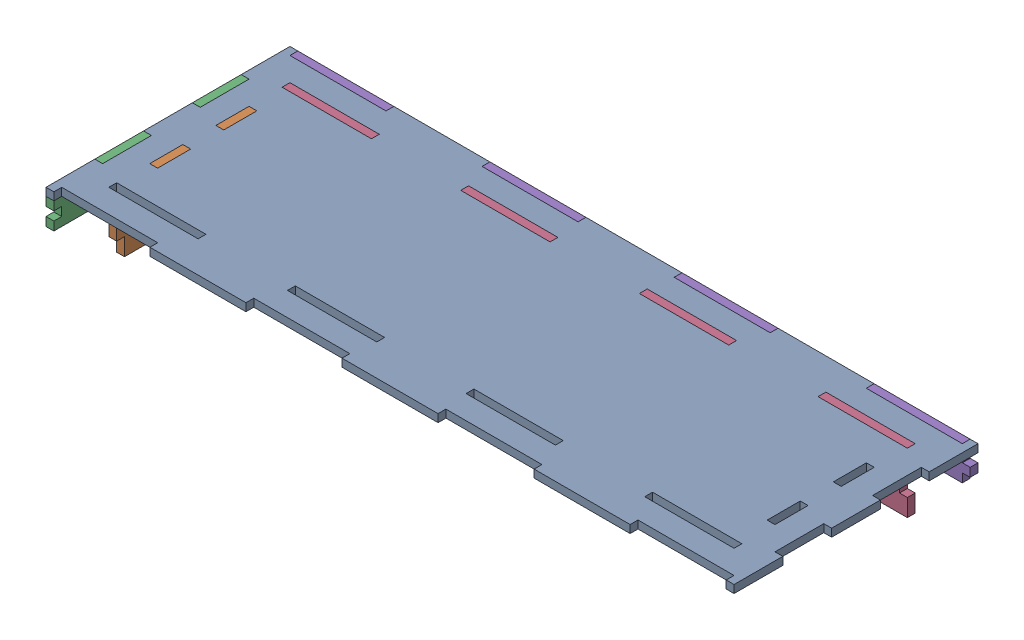
SolidWorks assembly lid, configuration Default. Lengths in mm.
Overall size (526 46 186.5).
5 component instances, 5 part files, 13 mates.
Components (placement in the parent):
- hood_top-1: hood_top [Default] at origin size (526 6 186.5)
- hood_front_inner-1: hood_front_inner [Default] at (-25.5 -6 0) size (6 46 138.5)
- hood_front_outer-1: hood_front_outer [Default] at (-25.5 -6 0) size (6 26 186.5)
- hood_side_inner-1: hood_side_inner [Default] at (0 -6 0) size (478 46 6)
- hood_side_outer-1: hood_side_outer [Default] at (0 -6 0) size (526 26 6)
Mates (geometry in assembly coordinates):
- Coincident1: coordinate: point of hood_top-1
- Coincident2: coincident anti-aligned: plane of hood_top-1 through (-233 6 63.25) normal (-1 0 0); plane of hood_front_inner-1 through (-233 -40 0) normal (1 0 0)
- Coincident3: coincident anti-aligned: plane of hood_top-1 through (0 0 37.95) normal (0 0 -1); plane of hood_front_inner-1 through (-25.5 6 37.95) normal (0 0 1)
- Coincident4: coincident aligned: plane of hood_top-1 through (0 6 0) normal (0 1 0); plane of hood_front_inner-1 through (-25.5 6 0) normal (0 1 0)
- Coincident7: coincident aligned: plane of hood_top-1 through (0 6 0) normal (0 1 0); plane of hood_side_outer-1 through (0 6 0) normal (0 1 0)
- Coincident8: coincident aligned: plane of hood_top-1 through (0 0 -93.25) normal (0 0 -1); plane of hood_side_outer-1 through (0 -20 -93.25) normal (0 0 -1)
- Coincident9: coincident anti-aligned: plane of hood_top-1 through (-257 0 0) normal (1 0 0); plane of hood_side_outer-1 through (-257 -20 0) normal (-1 0 0)
- Coincident10: coincident anti-aligned: plane of hood_top-1 through (-257 0 0) normal (-1 0 0); plane of hood_front_outer-1 through (-257 -20 0) normal (1 0 0)
- Coincident11: coincident anti-aligned: plane of hood_front_outer-1 through (-25.5 -6 -87.25) normal (0 0 -1); plane of hood_side_outer-1 through (0 -20 -87.25) normal (0 0 1)
- Coincident12: coincident anti-aligned: plane of hood_front_outer-1 through (-25.5 -6.6667 -87.25) normal (0 -1 0); plane of hood_side_outer-1 through (-263 -6.6667 0) normal (0 1 0)
- Coincident13: coincident anti-aligned: plane of hood_top-1 through (-233 6 -63.25) normal (0 0 -1); plane of hood_side_inner-1 through (0 -40 -63.25) normal (0 0 1)
- Coincident14: coincident aligned: plane of hood_top-1 through (0 6 0) normal (0 1 0); plane of hood_side_inner-1 through (0 6 0) normal (0 1 0)
- Coincident15: coincident anti-aligned: plane of hood_top-1 through (170.7143 0 0) normal (1 0 0); plane of hood_side_inner-1 through (170.7143 6 0) normal (-1 0 0)
